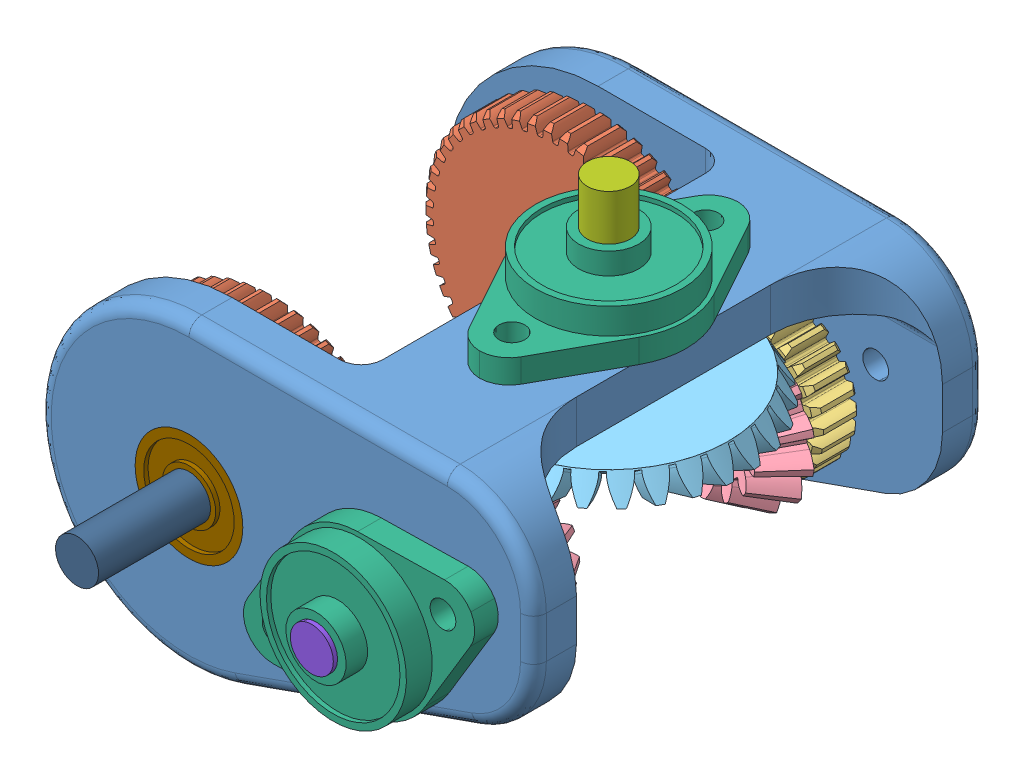
SolidWorks assembly ASSEMBLY Full Design 3rd Attempt - Holder Frame Design, configuration Default. Lengths in mm.
Overall size (122.07 107.14 157).
18 component instances, 10 part files, 47 mates.
Components (placement in the parent):
- Main Case-1: Main Case [Default] at (-4.7488 58.7631 49.9063) size (115 70 105)
- Secondary Big Spur Gear-1: Secondary Big Spur Gear [Default] at (-4.7488 58.7631 64.9063) x (-0.969554 -0.244877 0) z (0 0 1) size (62.4 62.32 10)
- Secondary Big Spur Gear-2: Secondary Big Spur Gear [Default] at (-4.7488 58.7631 139.9063) x (-1 0 0) z (0 0 1) size (62.4 62.32 10)
- Main Spur Gear - Copy-1: Main Spur Gear - Copy [Default] at (40.2512 58.7631 139.9063) x (0.999122 -0.041888 0) z (0 0 1) size (32.38 32.33 10)
- Main Spur Gear - Copy-2: Main Spur Gear - Copy [Default] at (40.2512 58.7631 64.9063) x (0.388972 -0.92125 0) z (0 0 1) size (32.38 32.33 10)
- Secondary Bevel Gear-1: Secondary Bevel Gear [Default] at (40.2512 58.7631 72.5284) x (-0.388972 0.92125 0) z (0.92125 0.388972 0) size (38.46 39.84 38.26)
- Secondary Bevel Gear-2: Secondary Bevel Gear [Default] at (40.2512 58.7631 132.2842) x (0.999122 -0.041888 0) z (0.041888 0.999122 0) size (38.46 39.84 38.26)
- Secondary Main Bevel Gear-1: Secondary Main Bevel Gear [Default] at (40.2512 76.0836 102.4063) x (-0.315294 0 0.948994) z (0.948994 0 0.315294) size (61.95 69.28 62)
- Main Slewing Bearing-1: Main Slewing Bearing [Default] at (40.2512 93.7631 102.4063) x (0 0 -1) z (1 0 0) size (60 15.5 36)
- Secondary Gear Shaft-1: Secondary Gear Shaft [Default] at (40.2512 119.8659 102.4063) x (0.315294 0 -0.948994) z (-0.948994 0 -0.315294) size (10 46 10)
- Secondary Gear Shaft Horizontal-1: Secondary Gear Shaft Horizontal [Default] at (40.2512 58.7631 171.3756) x (-0.999122 0.041888 0) z (-0.041888 -0.999122 0) size (10 46 10)
- Secondary Gear Shaft Horizontal-3: Secondary Gear Shaft Horizontal [Default] at (40.2512 58.7631 33.4369) x (0.388972 -0.92125 0) z (-0.92125 -0.388972 0) size (10 46 10)
- Main Slewing Bearing-2: Main Slewing Bearing [Default] at (40.2512 58.7631 49.9063) x (0.866025 0.5 0) z (-0.5 0.866025 0) size (60 15.5 36)
- Main Slewing Bearing-3: Main Slewing Bearing [Default] at (40.2512 58.7631 154.9063) x (0.866025 0.5 0) z (0.5 -0.866025 0) size (60 15.5 36)
- Main Bearing-1: Main Bearing [Default] at (-4.7488 58.7631 149.9063) size (25 25 10)
- Main Bearing-2: Main Bearing [Default] at (-4.7488 58.7631 54.9063) size (25 25 10)
- Secondary Gear Shaft Horizontal Back-1: Secondary Gear Shaft Horizontal Back [Default] at (-4.7488 58.7631 23.9063) x (-0.969554 -0.244877 0) z (-0.244877 0.969554 0) size (10 46 10)
- Secondary Gear Shaft Horizontal Back-2: Secondary Gear Shaft Horizontal Back [Default] at (-4.7488 58.7631 180.9063) x (1 0 0) z (0 1 0) size (10 46 10)
Mates (geometry in assembly coordinates):
- Concentric1: concentric aligned: cylinder of Main Case-1 through (-4.7488 58.7631 144.9063) axis (0 0 1) radius 12.5; cylinder of Secondary Big Spur Gear-2 through (-4.7488 58.7631 134.9063) axis (0 0 1) radius 5
- Coincident1: coincident anti-aligned: plane of Main Case-1 through (-4.7488 58.7631 144.9063) normal (0 0 -1); plane of Secondary Big Spur Gear-2 through (-4.7488 58.7631 144.9063) normal (0 0 1)
- Concentric2: concentric anti-aligned: cylinder of Main Case-1 through (-4.7488 58.7631 59.9063) axis (0 0 -1) radius 12.5; cylinder of Secondary Big Spur Gear-1 through (-4.7488 58.7631 59.9063) axis (0 0 1) radius 5
- Coincident2: coincident anti-aligned: plane of Main Case-1 through (-4.7488 58.7631 59.9063) normal (0 0 1); plane of Secondary Big Spur Gear-1 through (-4.7488 58.7631 59.9063) normal (0 0 -1)
- Concentric3: concentric anti-aligned: cylinder of Main Case-1 through (40.2512 58.7631 59.9063) axis (0 0 -1) radius 5; cylinder of Main Spur Gear - Copy-2 through (40.2512 58.7631 59.9063) axis (0 0 1) radius 5
- Coincident3: coincident anti-aligned: plane of Main Case-1 through (-4.7488 58.7631 59.9063) normal (0 0 1); plane of Main Spur Gear - Copy-2 through (40.2512 58.7631 59.9063) normal (0 0 -1)
- GearMate1: gear = 60 : 30 mm: circle of Main Spur Gear - Copy-2; circle of Secondary Big Spur Gear-1
- Concentric5: concentric aligned: cylinder of Main Case-1 through (40.2512 58.7631 144.9063) axis (0 0 1) radius 5; cylinder of Main Spur Gear - Copy-1 through (40.2512 58.7631 134.9063) axis (0 0 1) radius 5
- Coincident4: coincident anti-aligned: plane of Main Case-1 through (-4.7488 58.7631 144.9063) normal (0 0 -1); plane of Main Spur Gear - Copy-1 through (40.2512 58.7631 144.9063) normal (0 0 1)
- GearMate2: gear = 60 : 30 mm: circle of Main Spur Gear - Copy-1; circle of Secondary Big Spur Gear-2
- Concentric7: concentric aligned: cylinder of Main Case-1 through (40.2512 58.7631 59.9063) axis (0 0 -1) radius 5; cylinder of Secondary Bevel Gear-1 through (40.2512 58.7631 81.9869) axis (0 0 -1) radius 5
- Coincident5: coincident aligned: plane of Main Spur Gear - Copy-2 through (45.922 63.3284 59.9063) normal (-0.92125 -0.388972 0); plane of Secondary Bevel Gear-1 through (47.4779 59.6434 81.9869) normal (-0.92125 -0.388972 0)
- Concentric8: concentric aligned: cylinder of Main Spur Gear - Copy-1 through (40.2512 58.7631 134.9063) axis (0 0 1) radius 5; cylinder of Secondary Bevel Gear-2 through (40.2512 58.7631 122.8257) axis (0 0 1) radius 5
- Coincident6: coincident aligned: plane of Main Spur Gear - Copy-1 through (38.5462 65.8408 134.9063) normal (-0.041888 -0.999122 0); plane of Secondary Bevel Gear-2 through (38.5462 65.8408 122.8257) normal (-0.041888 -0.999122 0)
- Concentric9: concentric aligned: cylinder of Main Case-1 through (40.2512 23.7631 102.4063) axis (0 1 0) radius 5; cylinder of Secondary Main Bevel Gear-1 through (40.2512 69.8591 102.4063) axis (0 1 0) radius 5
- Coincident7: coincident: point of Secondary Bevel Gear-1; point of Secondary Main Bevel Gear-1
- Coincident8: coincident: line of Secondary Bevel Gear-2 through (40.2512 58.7631 102.4063) axis (-0.499561 0.020944 0.866025)
- GearMate3: gear = 34.5 : 60 mm: circle of Secondary Main Bevel Gear-1; circle of Secondary Bevel Gear-1
- GearMate4: gear = 60 : 34.5 mm: circle of Secondary Bevel Gear-2; circle of Secondary Main Bevel Gear-1
- Concentric11: concentric aligned: cylinder of Main Case-1 through (40.2512 23.7631 102.4063) axis (0 1 0) radius 5; cylinder of Main Slewing Bearing-1 through (40.2512 93.7631 102.4063) axis (0 1 0) radius 5
- Concentric12: concentric anti-aligned: cylinder of Main Case-1 through (40.2512 93.7631 79.9063) axis (0 1 0) radius 3; cylinder of Main Slewing Bearing-1 through (40.2512 99.2631 79.9063) axis (0 -1 0) radius 3
- Coincident9: coincident anti-aligned: plane of Main Case-1 through (-4.7488 93.7631 59.9063) normal (0 1 0); plane of Main Slewing Bearing-1 through (40.2512 93.7631 102.4063) normal (0 -1 0)
- Concentric13: concentric aligned: cylinder of Main Slewing Bearing-1 through (40.2512 93.7631 102.4063) axis (0 1 0) radius 5; cylinder of Secondary Gear Shaft-1 through (40.2512 73.8659 102.4063) axis (0 1 0) radius 5
- Coincident10: coincident aligned: plane of Secondary Main Bevel Gear-1 through (46.4791 73.8659 83.6612) normal (0 -1 0); plane of Secondary Gear Shaft-1 through (40.2512 73.8659 102.4063) normal (0 -1 0)
- Coincident11: coincident aligned: plane of Secondary Main Bevel Gear-1 through (45.2307 69.8591 101.9532) normal (-0.315294 0 0.948994); plane of Secondary Gear Shaft-1 through (43.7288 83.8659 101.4542) normal (-0.315294 0 0.948994)
- Concentric14: concentric aligned: cylinder of Secondary Bevel Gear-1 through (40.2512 58.7631 81.9869) axis (0 0 -1) radius 5; cylinder of Secondary Gear Shaft Horizontal-3 through (40.2512 58.7631 79.4369) axis (0 0 -1) radius 5
- Coincident12: coincident aligned: plane of Secondary Bevel Gear-1 through (43.8532 50.2321 79.4369) normal (0 0 1); plane of Secondary Gear Shaft Horizontal-3 through (40.2512 58.7631 79.4369) normal (0 0 1)
- Coincident15: coincident aligned: plane of Secondary Bevel Gear-1 through (45.2509 58.7031 81.9869) normal (-0.388972 0.92125 0); plane of Secondary Gear Shaft Horizontal-3 through (43.7929 58.0875 69.4369) normal (-0.388972 0.92125 0)
- Concentric15: concentric aligned: cylinder of Secondary Bevel Gear-2 through (40.2512 58.7631 122.8257) axis (0 0 1) radius 5; cylinder of Secondary Gear Shaft Horizontal-1 through (40.2512 58.7631 125.3756) axis (0 0 1) radius 5
- Coincident16: coincident aligned: plane of Secondary Bevel Gear-2 through (30.9991 59.151 125.3756) normal (0 0 -1); plane of Secondary Gear Shaft Horizontal-1 through (40.2512 58.7631 125.3756) normal (0 0 -1)
- Coincident17: coincident aligned: plane of Secondary Bevel Gear-2 through (38.445 63.4255 122.8257) normal (0.999122 -0.041888 0); plane of Secondary Gear Shaft Horizontal-1 through (38.3787 61.8443 135.3756) normal (0.999122 -0.041888 0)
- Concentric16: concentric aligned: cylinder of Secondary Gear Shaft Horizontal-3 through (40.2512 58.7631 79.4369) axis (0 0 -1) radius 5; cylinder of Main Slewing Bearing-2 through (40.2512 58.7631 49.9063) axis (0 0 -1) radius 5
- Coincident18: coincident anti-aligned: plane of Main Case-1 through (-4.7488 58.7631 49.9063) normal (0 0 -1); plane of Main Slewing Bearing-2 through (40.2512 58.7631 49.9063) normal (0 0 1)
- Concentric17: concentric anti-aligned: cylinder of Main Case-1 through (59.7368 70.0131 154.9063) axis (0 0 -1) radius 3; cylinder of Main Slewing Bearing-2 through (59.7368 70.0131 44.4063) axis (0 0 1) radius 3
- Concentric18: concentric aligned: cylinder of Secondary Gear Shaft Horizontal-1 through (40.2512 58.7631 125.3756) axis (0 0 1) radius 5; cylinder of Main Slewing Bearing-3 through (40.2512 58.7631 154.9063) axis (0 0 1) radius 5
- Concentric19: concentric aligned: cylinder of Main Case-1 through (59.7368 70.0131 154.9063) axis (0 0 -1) radius 3; cylinder of Main Slewing Bearing-3 through (59.7368 70.0131 160.4063) axis (0 0 -1) radius 3
- Coincident19: coincident anti-aligned: plane of Main Case-1 through (-4.7488 58.7631 154.9063) normal (0 0 1); plane of Main Slewing Bearing-3 through (40.2512 58.7631 154.9063) normal (0 0 -1)
- Concentric20: concentric anti-aligned: cylinder of Main Case-1 through (-4.7488 58.7631 144.9063) axis (0 0 1) radius 12.5; cylinder of Main Bearing-1 through (-4.7488 58.7631 154.9063) axis (0 0 -1) radius 12.5
- Coincident20: coincident aligned: plane of Main Case-1 through (-4.7488 58.7631 154.9063) normal (0 0 1); plane of Main Bearing-1 through (-4.7488 58.7631 154.9063) normal (0 0 1)
- Concentric21: concentric aligned: cylinder of Main Case-1 through (-4.7488 58.7631 59.9063) axis (0 0 -1) radius 12.5; cylinder of Main Bearing-2 through (-4.7488 58.7631 59.9063) axis (0 0 -1) radius 5
- Coincident21: coincident aligned: plane of Main Case-1 through (-4.7488 58.7631 49.9063) normal (0 0 -1); plane of Main Bearing-2 through (-4.7488 58.7631 49.9063) normal (0 0 -1)
- Concentric22: concentric aligned: cylinder of Main Bearing-2 through (-4.7488 58.7631 59.9063) axis (0 0 -1) radius 5; cylinder of Secondary Gear Shaft Horizontal Back-1 through (-4.7488 58.7631 69.9063) axis (0 0 -1) radius 5
- Coincident22: coincident aligned: plane of Secondary Big Spur Gear-1 through (-4.7488 58.7631 69.9063) normal (0 0 1); plane of Secondary Gear Shaft Horizontal Back-1 through (-4.7488 58.7631 69.9063) normal (0 0 1)
- Coincident23: coincident aligned: plane of Secondary Big Spur Gear-1 through (-1.6875 54.8098 59.9063) normal (-0.969554 -0.244877 0); plane of Secondary Gear Shaft Horizontal Back-1 through (-2.075 56.3442 59.9063) normal (-0.969554 -0.244877 0)
- Concentric23: concentric anti-aligned: cylinder of Main Bearing-1 through (-4.7488 58.7631 154.9063) axis (0 0 -1) radius 5; cylinder of Secondary Gear Shaft Horizontal Back-2 through (-4.7488 58.7631 134.9063) axis (0 0 1) radius 5
- Coincident24: coincident aligned: plane of Secondary Big Spur Gear-2 through (-4.7488 58.7631 134.9063) normal (0 0 -1); plane of Secondary Gear Shaft Horizontal Back-2 through (-4.7488 58.7631 134.9063) normal (0 0 -1)
- Coincident25: coincident aligned: plane of Secondary Big Spur Gear-2 through (-2.7488 54.1805 134.9063) normal (-1 0 0); plane of Secondary Gear Shaft Horizontal Back-2 through (-2.7488 55.7631 144.9063) normal (-1 0 0)
